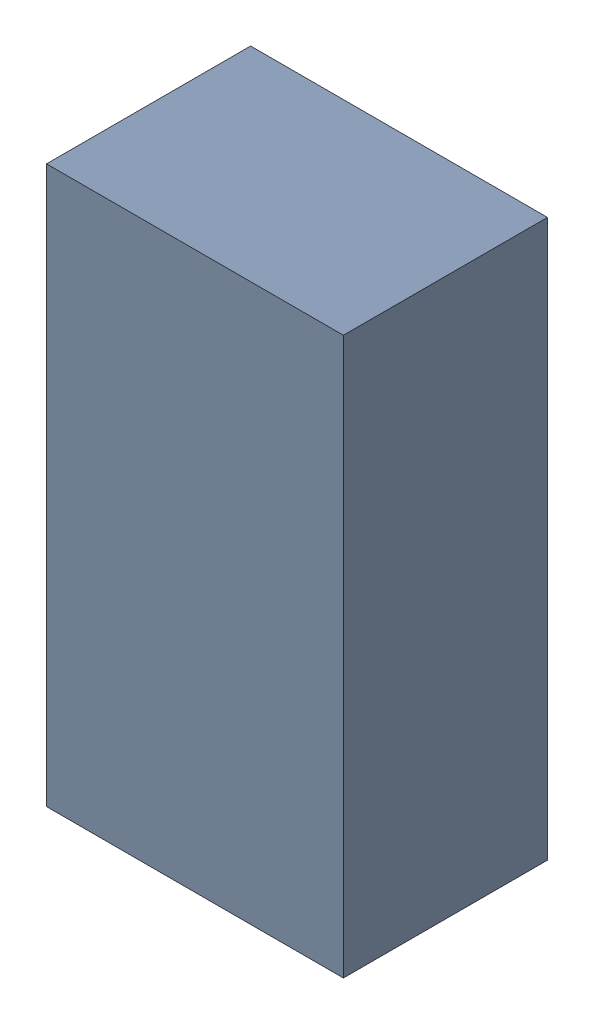
SolidWorks assembly U7, configuration Default. Lengths in mm.
Overall size (1.6 3 1.1).
2 component instances, 1 part files, 0 mates.
Components (placement in the parent):
- 870944800-1: 870944800 [Default] at (65.913 27.94 0) size (1.6 3 1.1)
  - Extruded_17-1: Extruded_17 [Default] at origin size (1.6 3 1.1)
